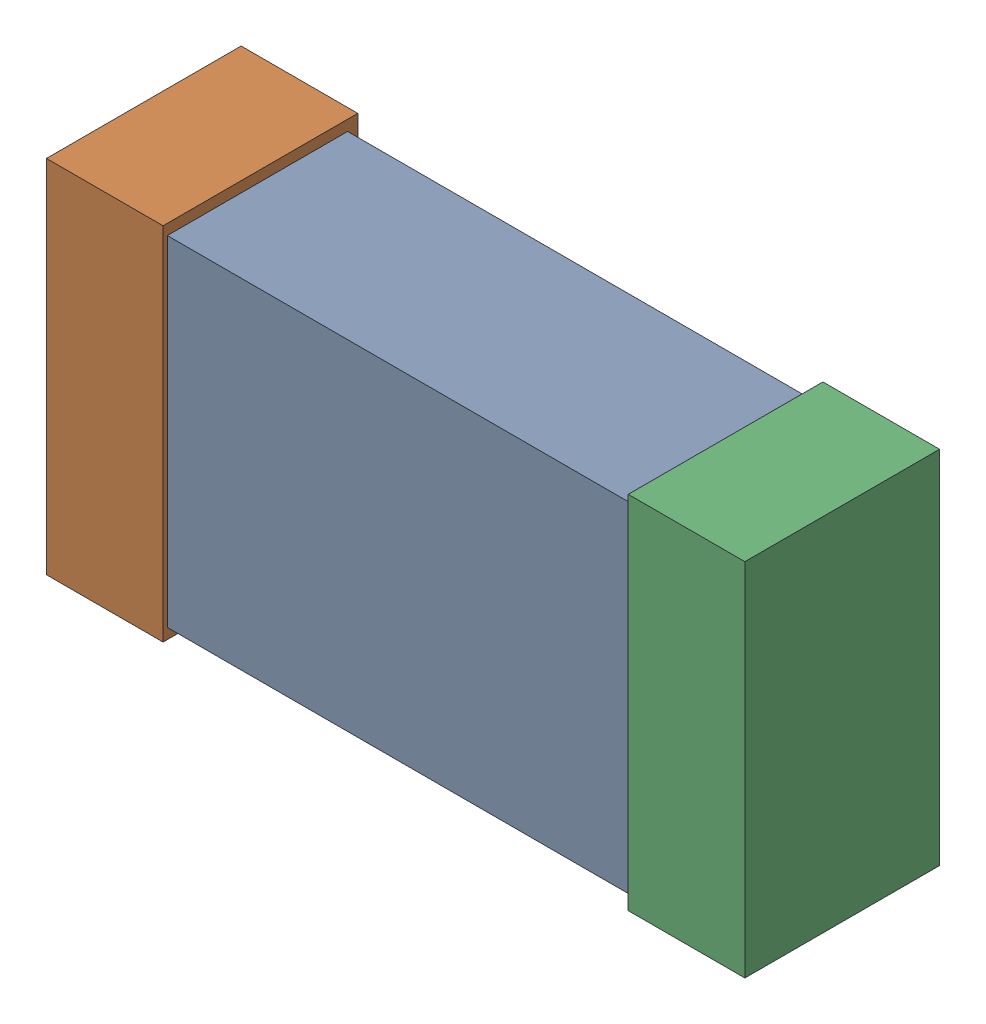
SolidWorks assembly R10, configuration Default. Lengths in mm.
Overall size (1.65 0.85 0.46).
6 component instances, 2 part files, 0 mates.
Components (placement in the parent):
- 432120720_16-1: 432120720_16 [Default] at (28.5459 19.8613 0.025) size (1.5 0.8 0.42)
  - Extruded (12)-1: Extruded (12) [Default] at origin size (1.5 0.8 0.42)
- 432120464_34-1: 432120464_34 [Default] at (27.8601 19.8613 0.001) size (0.28 0.85 0.46)
  - Extruded (11)-1: Extruded (11) [Default] at origin size (0.28 0.85 0.46)
- 432120464_35-1: 432120464_35 [Default] at (29.2316 19.8613 0.001) size (0.28 0.85 0.46)
  - Extruded (11)-1: Extruded (11) [Default] at origin size (0.28 0.85 0.46)
